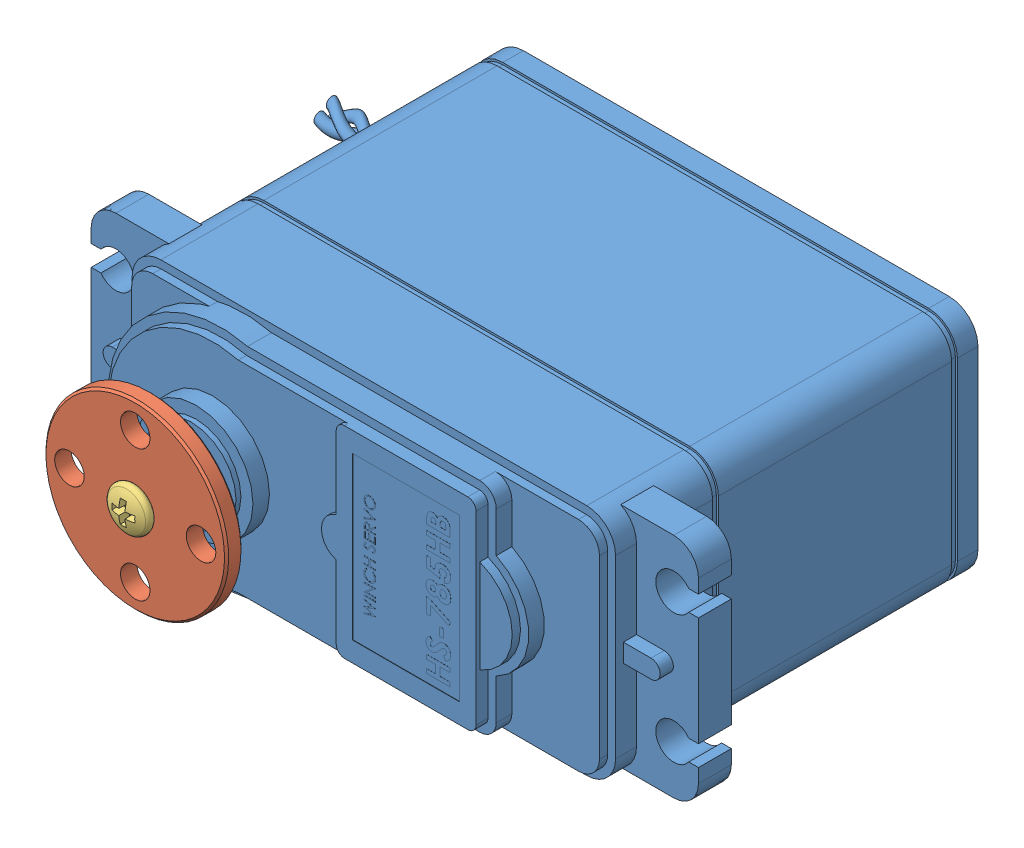
SolidWorks assembly Tetrix Servo Large 1260° (with Horn), configuration Default. Lengths in mm.
Overall size (82.28 28.4 60.55).
4 component instances, 3 part files, 0 mates.
Components (placement in the parent):
- Tetrix Servo Large 1260°-1: Tetrix Servo Large 1260° [Default] at origin size (82.28 28.4 55.3)
- Tetrix Servo Horn (with Screw)-1: Tetrix Servo Horn (with Screw) [Default] at (-15.725 0 18.875) x (-1 0 0) z (0 1 0) size (22.2 11.58 22.2)
  - Tetrix Servo Horn-1: Tetrix Servo Horn [Default] at origin size (22.2 6.2 22.2)
  - Tetrix Servo Screw-1: Tetrix Servo Screw [Default] at (0 -3.6552 0) size (5.25 11.58 5.25)
